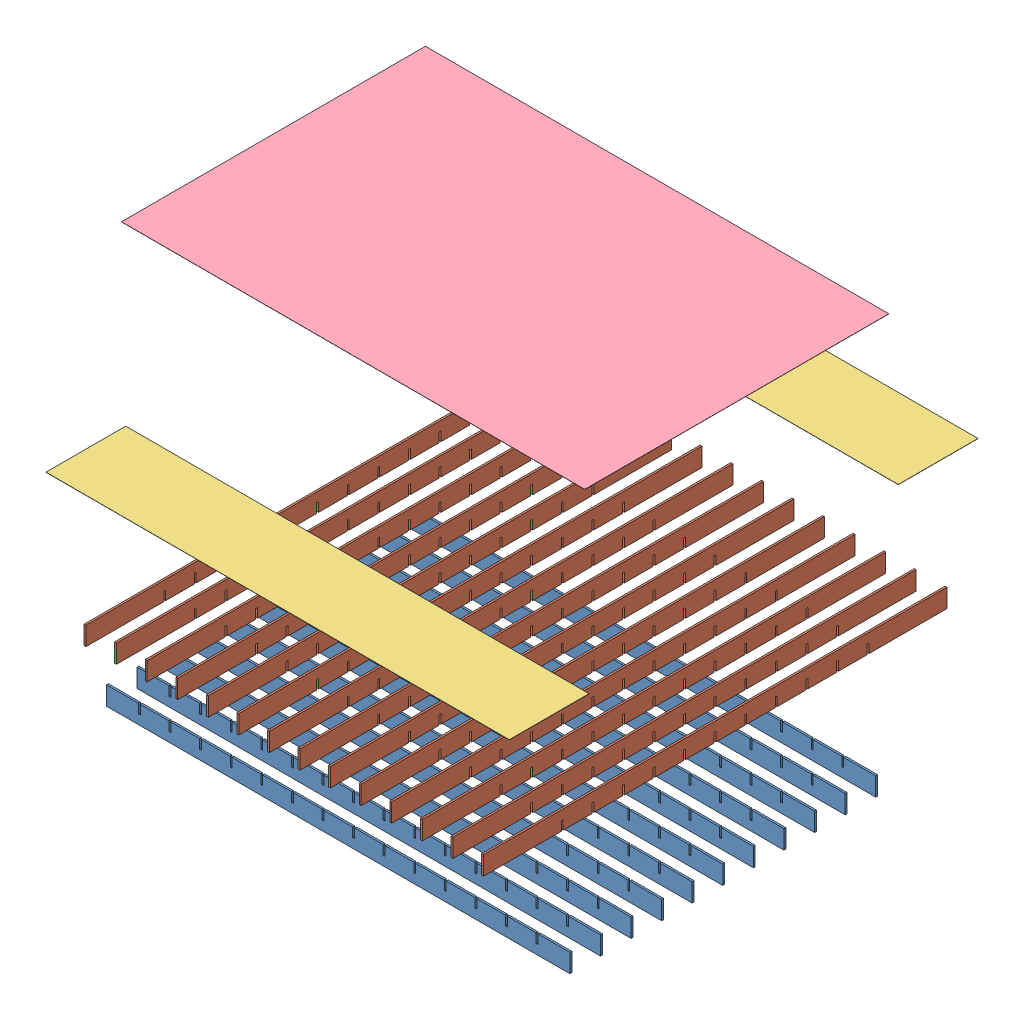
SolidWorks assembly Arbalet_GRID_ASM, configuration vu éclatée. Lengths in mm.
Overall size (580.82 363.89 545.81).
28 component instances, 4 part files, 14 mates.
Components (placement in the parent):
- Arbalet_GRID_14-1: Arbalet_GRID_14 [Défaut] at (-43.1706 54.9227 480) size (500 20 2)
- Arbalet_GRID_11-1: Arbalet_GRID_11 [Défaut] at (-266.194 149.6913 281.2428) x (0 0 -1) z (-1 0 0) size (500 20 2)
- Arbalet_GRID_COVER-1: Arbalet_GRID_COVER [Défaut] at (-83.235 284.7043 43.5579) size (500 0.2 86)
- Arbalet_GRID_COVER-2: Arbalet_GRID_COVER [Défaut] at (-43.1706 296.1584 503.3698) size (500 0.2 86)
- Arbalet_GRID_11-14: Arbalet_GRID_11 [Défaut] at (-233.194 149.6913 281.2428) x (0 0 -1) z (-1 0 0) size (500 20 2)
- Arbalet_GRID_11-15: Arbalet_GRID_11 [Défaut] at (-200.194 149.6913 281.2428) x (0 0 -1) z (-1 0 0) size (500 20 2)
- Arbalet_GRID_11-16: Arbalet_GRID_11 [Défaut] at (-167.194 149.6913 281.2428) x (0 0 -1) z (-1 0 0) size (500 20 2)
- Arbalet_GRID_11-17: Arbalet_GRID_11 [Défaut] at (-134.194 149.6913 281.2428) x (0 0 -1) z (-1 0 0) size (500 20 2)
- Arbalet_GRID_11-18: Arbalet_GRID_11 [Défaut] at (-101.194 149.6913 281.2428) x (0 0 -1) z (-1 0 0) size (500 20 2)
- Arbalet_GRID_11-19: Arbalet_GRID_11 [Défaut] at (-68.194 149.6913 281.2428) x (0 0 -1) z (-1 0 0) size (500 20 2)
- Arbalet_GRID_11-20: Arbalet_GRID_11 [Défaut] at (-35.194 149.6913 281.2428) x (0 0 -1) z (-1 0 0) size (500 20 2)
- Arbalet_GRID_11-21: Arbalet_GRID_11 [Défaut] at (-2.194 149.6913 281.2428) x (0 0 -1) z (-1 0 0) size (500 20 2)
- Arbalet_GRID_11-22: Arbalet_GRID_11 [Défaut] at (30.806 149.6913 281.2428) x (0 0 -1) z (-1 0 0) size (500 20 2)
- Arbalet_GRID_11-23: Arbalet_GRID_11 [Défaut] at (63.806 149.6913 281.2428) x (0 0 -1) z (-1 0 0) size (500 20 2)
- Arbalet_GRID_11-24: Arbalet_GRID_11 [Défaut] at (96.806 149.6913 281.2428) x (0 0 -1) z (-1 0 0) size (500 20 2)
- Arbalet_GRID_11-25: Arbalet_GRID_11 [Défaut] at (129.806 149.6913 281.2428) x (0 0 -1) z (-1 0 0) size (500 20 2)
- Arbalet_GRID_11-26: Arbalet_GRID_11 [Défaut] at (162.806 149.6913 281.2428) x (0 0 -1) z (-1 0 0) size (500 20 2)
- Arbalet_GRID_14-11: Arbalet_GRID_14 [Défaut] at (-43.1706 54.9227 447) size (500 20 2)
- Arbalet_GRID_14-12: Arbalet_GRID_14 [Défaut] at (-43.1706 54.9227 414) size (500 20 2)
- Arbalet_GRID_14-13: Arbalet_GRID_14 [Défaut] at (-43.1706 54.9227 381) size (500 20 2)
- Arbalet_GRID_14-14: Arbalet_GRID_14 [Défaut] at (-43.1706 54.9227 348) size (500 20 2)
- Arbalet_GRID_14-15: Arbalet_GRID_14 [Défaut] at (-43.1706 54.9227 315) size (500 20 2)
- Arbalet_GRID_14-16: Arbalet_GRID_14 [Défaut] at (-43.1706 54.9227 282) size (500 20 2)
- Arbalet_GRID_14-17: Arbalet_GRID_14 [Défaut] at (-43.1706 54.9227 249) size (500 20 2)
- Arbalet_GRID_14-18: Arbalet_GRID_14 [Défaut] at (-43.1706 54.9227 216) size (500 20 2)
- Arbalet_GRID_14-19: Arbalet_GRID_14 [Défaut] at (-43.1706 54.9227 183) size (500 20 2)
- Arbalet_GRID_14-20: Arbalet_GRID_14 [Défaut] at (-43.1706 54.9227 150) size (500 20 2)
- Arbalet_GRID_Diffuser-1: Arbalet_GRID_Diffuser [Défaut] at (-123.9861 408.6165 220.0853) size (500 0.2 328)
Mates (geometry in assembly coordinates):
- Perpendiculaire1: perpendicular: plane of Arbalet_GRID_14-1 through (-43.1706 54.9227 481) normal (0 0 1); plane of Arbalet_GRID_11-1 through (-267.194 149.6913 281.2428) normal (-1 0 0)
- Coïncidente51: coincident anti-aligned: plane of Arbalet_GRID_COVER-2 through (-43.1706 110.717 525.25) normal (0 -1 0); plane of Arbalet_GRID_11-1 through (-242.1706 110.717 571.5) normal (0 1 0)
- Coïncidente9: coincident aligned: plane of Arbalet_GRID_14-1 through (-293.1706 44.9227 481) normal (-1 0 0); plane of Arbalet_GRID_COVER-2 through (-293.1706 296.3584 546.3698) normal (-1 0 0)
- Coïncidente52: coincident aligned: plane of Arbalet_GRID_11-1 through (-258.6706 64.9227 565) normal (0 0 1); plane of Arbalet_GRID_COVER-2 through (-293.1706 65.1227 565) normal (0 0 1)
- Coïncidente54: coincident anti-aligned: plane of Arbalet_GRID_14-1 through (-256.6706 54.9227 479) normal (0 1 0); plane of Arbalet_GRID_11-1 through (-256.6706 54.9227 481) normal (0 -1 0)
- Coïncidente56: coincident anti-aligned: plane of Arbalet_GRID_14-1 through (-256.6706 54.9227 479) normal (0 1 0); plane of Arbalet_GRID_11-1 through (-256.6706 54.9227 481) normal (0 -1 0)
- Coïncidente57: coincident anti-aligned: plane of Arbalet_GRID_14-1 through (-258.6706 54.9227 479) normal (1 0 0); plane of Arbalet_GRID_11-1 through (-258.6706 54.9227 315) normal (-1 0 0)
- Coïncidente58: coincident anti-aligned: plane of Arbalet_GRID_14-1 through (-43.1706 54.9227 481) normal (0 0 1); plane of Arbalet_GRID_11-1 through (-256.6706 54.9227 481) normal (0 0 -1)
- Coïncidente59: coincident aligned: plane of Arbalet_GRID_COVER-1 through (-293.1706 65.1227 65) normal (0 0 -1); plane of Arbalet_GRID_11-25 through (137.3294 64.9227 65) normal (0 0 -1)
- Coïncidente60: coincident aligned: plane of Arbalet_GRID_COVER-1 through (206.8294 65.1227 151) normal (1 0 0); plane of Arbalet_GRID_14-20 through (206.8294 44.9227 151) normal (1 0 0)
- Coïncidente61: coincident anti-aligned: plane of Arbalet_GRID_COVER-1 through (-43.1706 64.9227 108) normal (0 -1 0); plane of Arbalet_GRID_14-20 through (-293.1706 64.9227 151) normal (0 1 0)
- Coïncidente62: coincident aligned: plane of Arbalet_GRID_14-17 through (-293.1706 44.9227 250) normal (-1 0 0); plane of Arbalet_GRID_Diffuser-1 through (-293.1706 65.1227 479) normal (-1 0 0)
- Coïncidente63: coincident anti-aligned: plane of Arbalet_GRID_14-17 through (-293.1706 64.9227 250) normal (0 1 0); plane of Arbalet_GRID_Diffuser-1 through (-43.1706 64.9227 315) normal (0 -1 0)
- Coïncidente64: coincident anti-aligned: plane of Arbalet_GRID_COVER-1 through (-293.1706 65.1227 151) normal (0 0 1); plane of Arbalet_GRID_Diffuser-1 through (-293.1706 65.1227 151) normal (0 0 -1)
